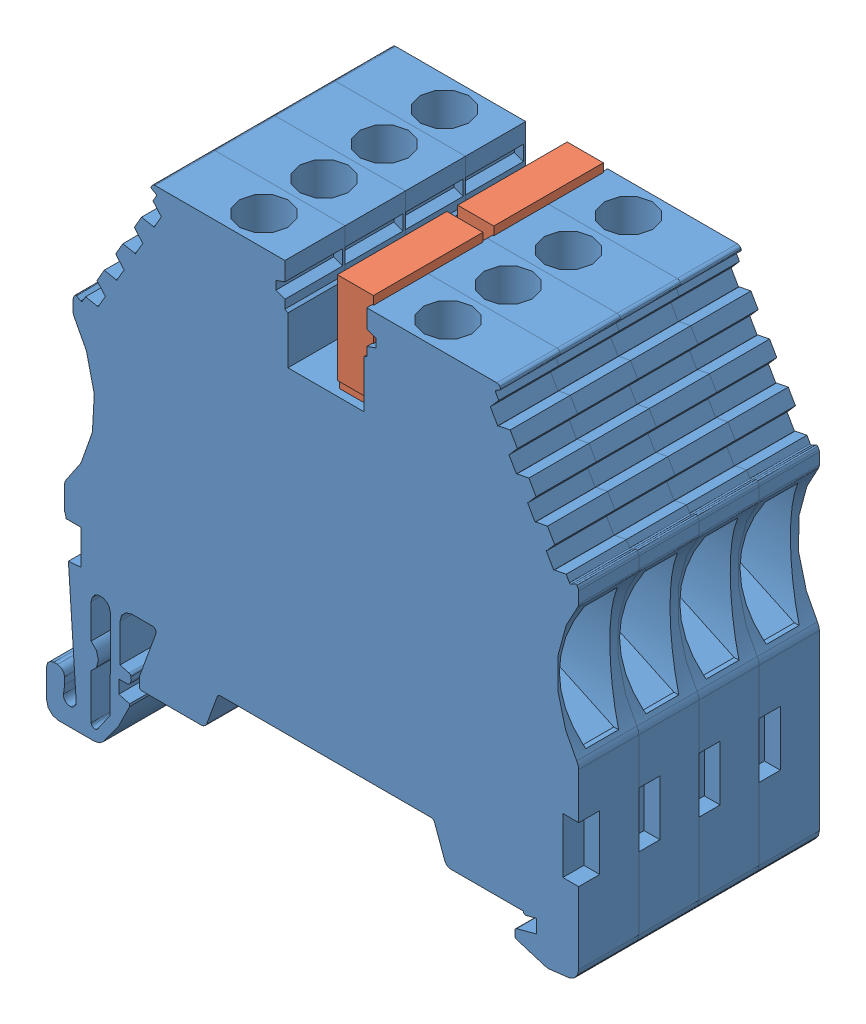
SolidWorks assembly terminalBlocks, configuration 4_Red. Lengths in mm.
Overall size (44.2 43.21 20).
11 component instances, 2 part files, 33 mates.
Components (placement in the parent):
- DIN_Terminal-1: DIN_Terminal [DIN_red] at (0 12.5 0) size (44.2 42.5 5)
- DIN_Terminal-3: DIN_Terminal [DIN_red] at (0 12.5 5) size (44.2 42.5 5)
- DIN_Terminal-4: DIN_Terminal [Default] at (0 12.5 10)
- DIN_Terminal-5: DIN_Terminal [Default] at (0 12.5 15)
- DIN_jumper-1: DIN_jumper [Default] at (2 30.6039 2.5) x (0 0 1) z (-1 0 0)
- DIN_jumper-2: DIN_jumper [Default] at (2 30.6039 12.5) x (0 0 1) z (-1 0 0)
- DIN_Terminal-6: DIN_Terminal [Default] at (0 12.5 20) (suppressed, hidden)
- DIN_Terminal-8: DIN_Terminal [Default] at (0 12.5 25) (suppressed, hidden)
- DIN_Terminal-9: DIN_Terminal [Default] at (0 12.5 30) (suppressed, hidden)
- DIN_jumper-3: DIN_jumper [Default] at (2 30.6039 27.5) x (0 0 1) z (-1 0 0) (suppressed, hidden)
- DIN_jumper-5: DIN_jumper [Default] at (-2 30.6039 17.5) x (0 0 1) z (-1 0 0) (suppressed, hidden)
Mates (geometry in assembly coordinates):
- Coincident1: coincident aligned: plane of DIN_Terminal-1 through (0 12.5 0) normal (0 0 1)
- Coincident2: coincident aligned: plane of DIN_Terminal-1 through (0 12.5 0) normal (1 0 0)
- Coincident5: coincident aligned: plane of DIN_Terminal-3 through (0 12.5 5) normal (1 0 0)
- Coincident12: coincident aligned: plane of assembly through (0 12.5 0) normal (0 1 0); plane of DIN_Terminal-4 through (0 12.5 10) normal (0 1 0)
- Coincident6: coincident aligned: plane of DIN_Terminal-4 through (0 12.5 10) normal (1 0 0)
- Coincident7: coincident aligned: plane of DIN_Terminal-5 through (0 12.5 15) normal (1 0 0)
- Coincident9: coincident anti-aligned: plane of DIN_Terminal-1 through (14.1946 37.1996 2.5) normal (0 0 1); plane of DIN_Terminal-3 through (14.1946 37.1996 2.5) normal (0 0 -1)
- Coincident10: coincident anti-aligned: plane of DIN_Terminal-3 through (14.1946 37.1996 7.5) normal (0 0 1); plane of DIN_Terminal-4 through (14.1946 37.1996 7.5) normal (0 0 -1)
- Coincident11: coincident anti-aligned: plane of DIN_Terminal-4 through (14.1946 37.1996 12.5) normal (0 0 1); plane of DIN_Terminal-5 through (14.1946 37.1996 12.5) normal (0 0 -1)
- Coincident13: coincident aligned: plane of DIN_Terminal-5 through (0 12.5 15) normal (0 1 0)
- Coincident14: coincident aligned: plane of DIN_Terminal-3 through (0 12.5 5) normal (0 1 0)
- Coincident15: coincident aligned: plane of DIN_Terminal-1 through (0 12.5 0) normal (0 1 0)
- Distance1: distance = 2 mm anti-aligned: plane of DIN_jumper-1 through (2 30.6039 2.5) normal (-1 0 0)
- Distance2: distance = 0.7 mm aligned: plane of DIN_jumper-1 through (2 30.6039 2.5) normal (0 1 0); plane of DIN_Terminal-1 through (-3.15 29.9039 2.5) normal (0 1 0)
- Coincident16: coincident: line of DIN_Terminal-3 through (14.1946 37.4996 2.5) axis (-1 0 0); plane of DIN_jumper-1 through (2 30.6039 2.5) normal (0 0 1)
- Distance3: distance = 2 mm anti-aligned: plane of DIN_jumper-2 through (2 30.6039 12.5) normal (-1 0 0)
- Distance4: distance = 0.7 mm aligned: plane of DIN_jumper-2 through (2 30.6039 12.5) normal (0 1 0); plane of DIN_Terminal-1 through (-3.15 29.9039 2.5) normal (0 1 0)
- Coincident17: coincident: line of DIN_Terminal-4 through (14.1946 37.4996 12.5) axis (-1 0 0); plane of DIN_jumper-2 through (2 30.6039 12.5) normal (0 0 1)
- Coincident18: coincident aligned: plane of DIN_Terminal-6 through (0 12.5 20) normal (1 0 0)
- Coincident20: coincident aligned: plane of DIN_Terminal-6 through (0 12.5 20) normal (0 1 0)
- Coincident23: coincident aligned: plane of DIN_Terminal-8 through (0 12.5 25) normal (1 0 0)
- Coincident24: coincident aligned: plane of DIN_Terminal-8 through (0 12.5 25) normal (0 1 0)
- Coincident25: coincident aligned: plane of DIN_Terminal-9 through (0 12.5 30) normal (1 0 0)
- Coincident26: coincident aligned: plane of DIN_Terminal-9 through (0 12.5 30) normal (0 1 0)
- Coincident29: coincident anti-aligned: plane of DIN_Terminal-5 through (14.1946 37.1996 17.5) normal (0 0 1); plane of DIN_Terminal-6 through (14.1946 37.1996 17.5) normal (0 0 -1)
- Coincident30: coincident anti-aligned: plane of DIN_Terminal-6 through (14.1946 37.1996 22.5) normal (0 0 1); plane of DIN_Terminal-8 through (14.1946 37.1996 22.5) normal (0 0 -1)
- Coincident31: coincident anti-aligned: plane of DIN_Terminal-8 through (14.1946 37.1996 27.5) normal (0 0 1); plane of DIN_Terminal-9 through (14.1946 37.1996 27.5) normal (0 0 -1)
- Distance5: distance = 2 mm anti-aligned: plane of DIN_jumper-3 through (2 30.6039 27.5) normal (-1 0 0)
- Distance6: distance = 0.7 mm aligned: plane of DIN_jumper-3 through (2 30.6039 27.5) normal (0 1 0); plane of DIN_Terminal-1 through (-3.15 29.9039 2.5) normal (0 1 0)
- Coincident32: coincident aligned: plane of DIN_Terminal-8 through (14.1946 37.1996 27.5) normal (0 0 1); plane of DIN_jumper-3 through (2 30.6039 27.5) normal (0 0 1)
- Distance9: distance = 2 mm anti-aligned: plane of DIN_jumper-5 through (-2 30.6039 17.5) normal (-1 0 0)
- Distance10: distance = 0.7 mm aligned: plane of DIN_jumper-5 through (-2 30.6039 17.5) normal (0 1 0); plane of DIN_Terminal-1 through (-3.15 29.9039 2.5) normal (0 1 0)
- Coincident33: coincident aligned: plane of DIN_Terminal-5 through (14.1946 37.1996 17.5) normal (0 0 1); plane of DIN_jumper-5 through (-2 30.6039 17.5) normal (0 0 1)
